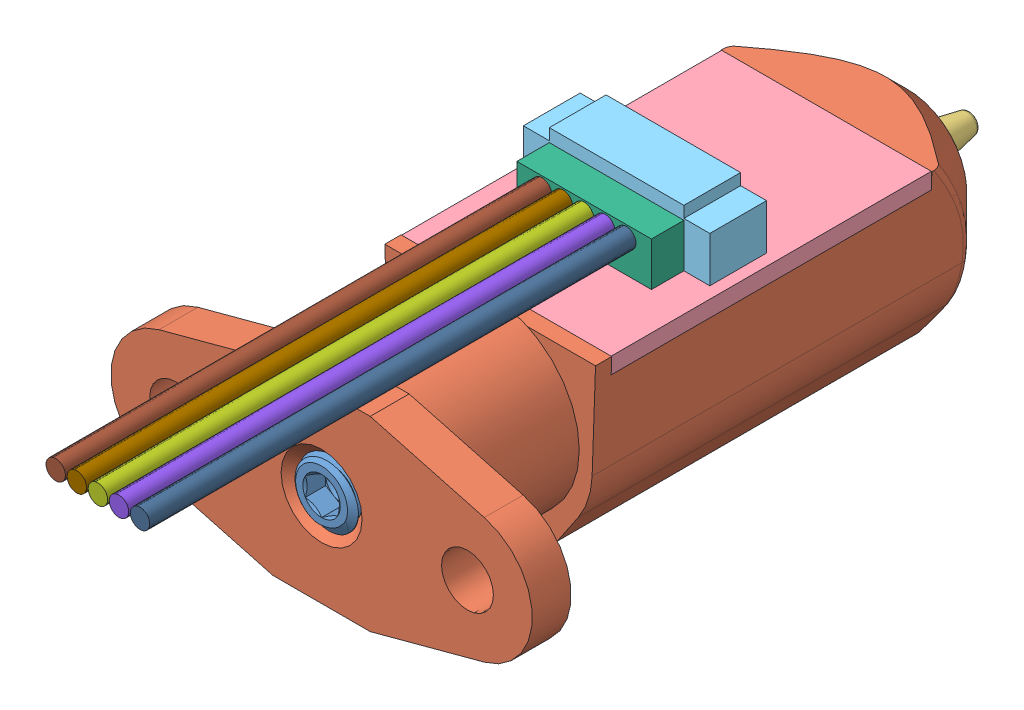
SolidWorks assembly BLTouch-Smart V3.1, configuration Default. Lengths in mm.
Overall size (26 15.35 53.8).
12 component instances, 11 part files, 0 mates.
Components (placement in the parent):
- BLTouch-Smart V3.1.step-1: BLTouch-Smart V3.1.step [Default] at origin size (26 15.35 53.8)
  - 93245A111.step-1: 93245A111.step [Default] at (0 0 -2.4994) size (4.11 4.11 5.12)
  - BL-touch.step-1: BL-touch.step [Default] at origin size (26 12.6 36.68)
  - BL-touch-0.step-1: BL-touch-0.step [Default] at origin size (2 2 10)
  - BL-touch-1.step-1: BL-touch-1.step [Default] at origin size (12.93 1 19.75)
  - BL-touch-2.step-1: BL-touch-2.step [Default] at origin size (11.5 3.5 3.5)
  - BL-touch-3.step-1: BL-touch-3.step [Default] at origin size (8.3 2.7 2)
  - BL-touch-4.step-1: BL-touch-4.step [Default] at origin size (1.2 1.2 30)
  - BL-touch-5.step-1: BL-touch-5.step [Default] at origin size (1.2 1.2 30)
  - BL-touch-6.step-1: BL-touch-6.step [Default] at origin size (1.2 1.2 30)
  - BL-touch-7.step-1: BL-touch-7.step [Default] at origin size (1.2 1.2 30)
  - BL-touch-8.step-1: BL-touch-8.step [Default] at origin size (1.2 1.2 30)
